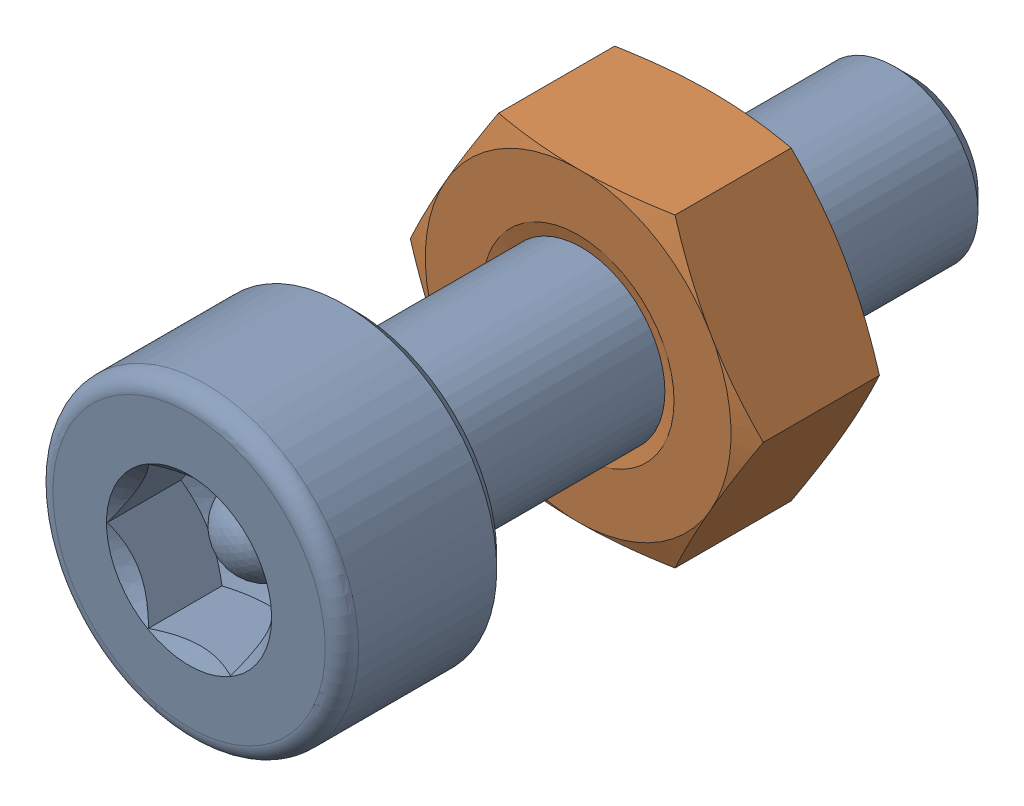
SolidWorks assembly Screw and Nut M3x010_019, configuration Varsayılan. Lengths in mm.
Overall size (6.35 5.5 13.14).
2 component instances, 2 part files, 0 mates.
Components (placement in the parent):
- M3x10-Screw018-1: M3x10-Screw018 [Varsayılan] at origin size (5.5 5.5 13.14)
- M3-Nut050-1: M3-Nut050 [Varsayılan] at (0 0 -4) x (-1 0 0) z (0 0 -1) size (6.35 5.5 2.4)
